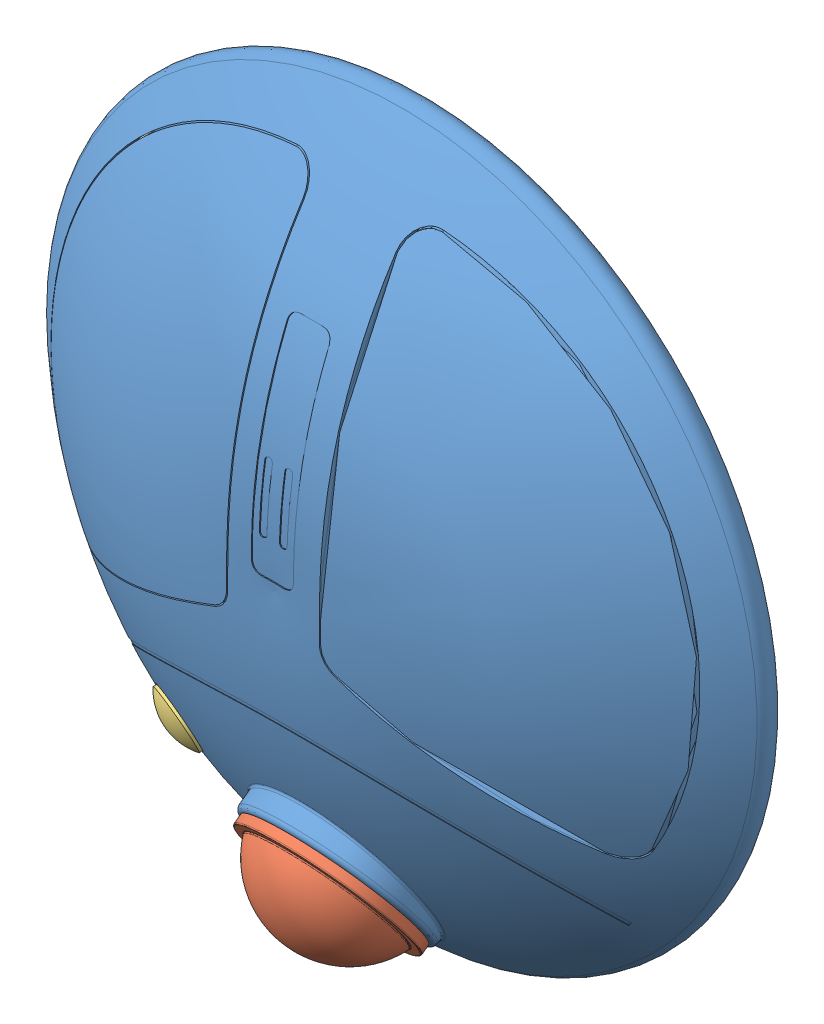
SolidWorks assembly lola, configuration Défaut. Lengths in mm.
Overall size (151.07 156.79 39.42).
3 component instances, 3 part files, 3 mates.
Components (placement in the parent):
- PièceModif-1: PièceModif [Défaut] at (-1.7304 -1.3563 138.4412) size (151.07 156.15 39.42)
- oeil-1: oeil [Défaut] at (-2.0589 -60.3602 155.3762) x (1 0 0) z (0 -0.596117 0.802898) size (34 34 17.25)
- lateraleye-1: lateraleye [Défaut] at (-36.1561 -48.1721 148.781) x (0.945757 -0.074359 0.316252) z (-0.315957 -0.437056 0.842112) size (12 12 7)
Mates (geometry in assembly coordinates):
- Parallèle1: parallel anti-aligned: plane of PièceModif-1 through (-2.0589 -60.3602 155.3762) normal (0 -0.596117 0.802898); plane of oeil-1 through (-2.0589 -57.3796 151.3617) normal (0 0.596117 -0.802898)
- Coïncidente2: coincident anti-aligned: plane of PièceModif-1 through (-2.0589 -60.3602 155.3762) normal (0 -0.596117 0.802898); plane of oeil-1 through (-2.0589 -60.3602 155.3762) normal (0 0.596117 -0.802898)
- Coaxiale1: concentric aligned: cylinder of PièceModif-1 through (-2.0589 -52.0145 144.1356) axis (0 -0.596117 0.802898) radius 13.7871; circle of oeil-1
